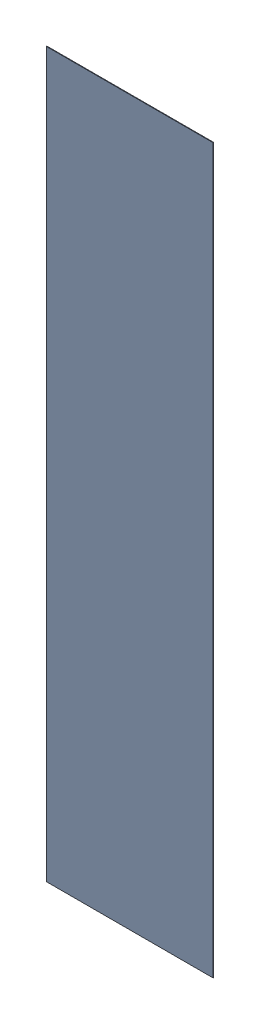
SolidWorks assembly HW2, configuration Default. Lengths in mm.
Overall size (3 13 0.01).
2 component instances, 1 part files, 0 mates.
Components (placement in the parent):
- 1088891232-1: 1088891232 [Default] at (13.875 24.5 -1.654) size (3 13 0.01)
  - Extruded-1: Extruded [Default] at origin size (3 13 0.01)
